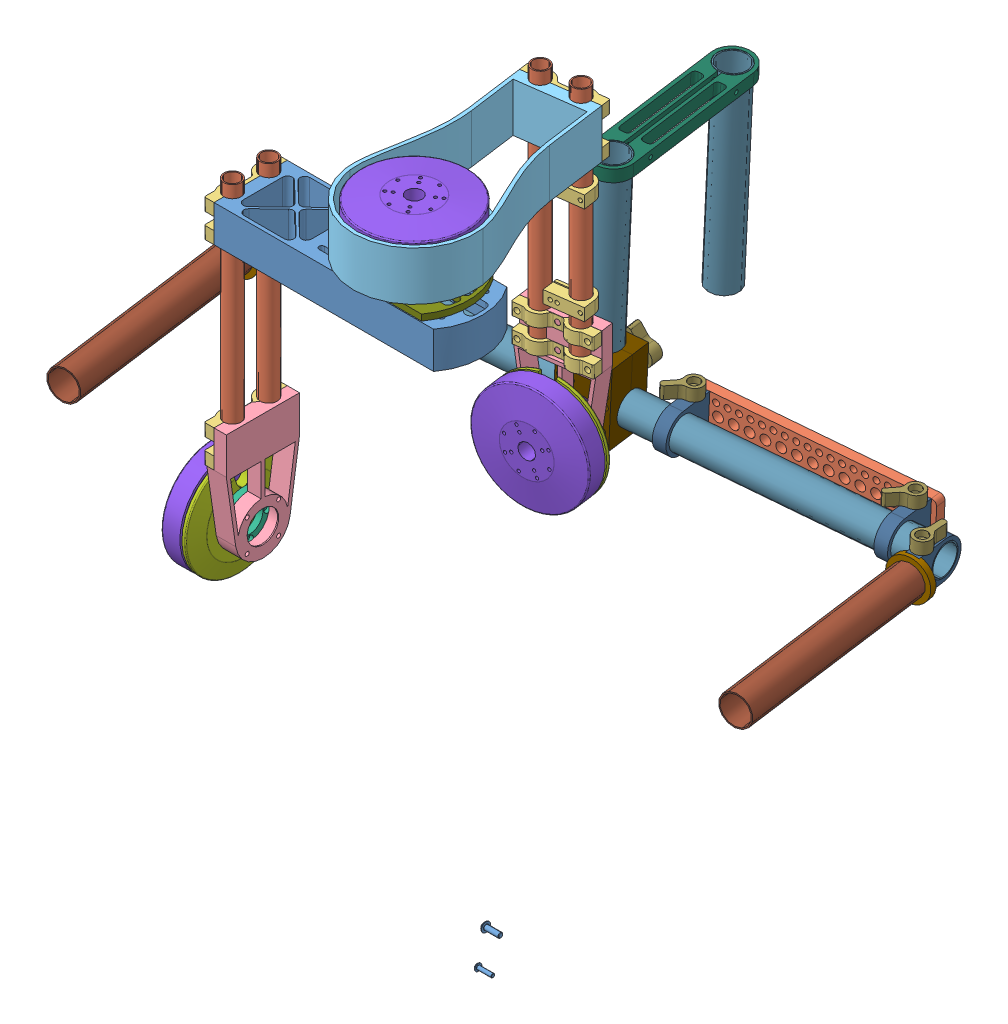
SolidWorks assembly Kinematik-3, configuration Default. Lengths in mm.
Overall size (547.61 521.51 375.61).
65 component instances, 21 part files, 73 mates.
Components (placement in the parent):
- Pitch_Roll-1: Pitch_Roll [Default] at (-118.8271 188.3671 50.6062) size (200.1 272.5 60)
  - Axis_roll-1: Axis_roll [Default] at (-7.781 -12.9874 24.4541) size (190 30 60)
  - Pipe_14mm-1: Pipe_14mm [200mm] at (-7.781 -172.9874 9.3541) size (14 200 14)
  - Pipe_14mm-2: Pipe_14mm [200mm] at (-7.781 -172.9874 -20.4459) x (0.999247 0 -0.038789) z (0.038789 0 0.999247) size (14 200 14)
  - Scoba_dowble-1: Scoba_dowble [Default] at (-7.781 7.0126 24.4541) size (10.1 10 60)
  - Scoba_dowble-4: Scoba_dowble [Default] at (-7.781 -12.9874 24.4541) size (10.1 10 60)
  - Axis_pitch-1: Axis_pitch [Default] at (-13.681 -142.9874 -35.5459) x (0 1 0) z (0 0 -1) size (102.5 16 60)
  - Scoba_dowble-5: Scoba_dowble [Default] at (-7.781 -152.9874 24.4541) size (10.1 10 60)
  - Scoba_dowble-6: Scoba_dowble [Default] at (-7.781 -172.9874 24.4541) size (10.1 10 60)
- Vert_rod_Yaw-1: Vert_rod_Yaw [Default] at (-64.2912 186.0394 -87.2214) x (0.99099 0 -0.133938) z (0.133938 0 0.99099) size (115.95 200 208.08)
  - Vert_rod-1: Vert_rod [Default] at (23.4777 34.3403 0.7123) size (100.16 40 190)
  - Pipe_14mm-1: Pipe_14mm [200mm] at (38.5777 84.3403 0.7123) x (0.837169 0 0.546944) z (0.546944 0 -0.837169) size (14 200 14)
  - Pipe_14mm-2: Pipe_14mm [200mm] at (68.3777 84.3403 0.7123) x (0.837169 0 0.546944) z (0.546944 0 -0.837169) size (14 200 14)
  - Scoba_dowble-1: Scoba_dowble [Default] at (23.4777 34.3403 0.7123) x (0 0 1) z (-1 0 0) size (10.1 10 60)
  - Scoba_dowble-2: Scoba_dowble [Default] at (83.4777 74.3403 0.7123) x (0 0 1) z (1 0 0) size (10.1 10 60)
  - Washer_bearings-1: Washer_bearings [Default] at (53.4777 45.3403 140.7123) x (0.707107 0 0.707107) z (-0.707107 0 0.707107) size (40.8 5 40.8)
  - Motor8190_DYS-1: Motor8190_DYS [Default] at (39.267 74.8347 138.3821) x (-1 0 0) z (0 0 1) size (115.95 27.6 115.95)
    - Stator-1: Stator [Default] at (-14.2107 17.4944 2.3302) size (87 7.3 86.61)
    - Rotor-1: Rotor [Default] at (-14.2107 15.8944 2.3302) x (0.429925 0 -0.902864) z (0 1 0) size (87 87 27.6)
- Washer_bearings-1: Washer_bearings [Default] at (-127.5081 -34.6203 45.0604) x (0 -0.707107 -0.707107) z (0 0.707107 -0.707107) size (40.8 5 40.8)
- Motor8190_DYS-1: Motor8190_DYS [Default] at (-157.0025 -32.2901 30.8496) x (0 0 -1) z (0 -1 0) size (115.95 27.6 115.95)
  - Stator-1: Stator [Default] at (-14.2107 17.4944 2.3302) size (87 7.3 86.61)
  - Rotor-1: Rotor [Default] at (-14.2107 15.8944 2.3302) x (0.429925 0 -0.902864) z (0 1 0) size (87 87 27.6)
- Axis_pitch-1: Axis_pitch [Default] at (-40.1394 100.3797 -83.8132) x (0 1 0) z (-0.99099 0 0.133938) size (102.5 16 60)
- Scoba_dowble-1: Scoba_dowble [Default] at (18.5497 90.3797 -97.547) x (-0.130612 0 -0.991434) z (0.991434 0 -0.130612) size (10.1 10 60)
- Scoba_dowble-2: Scoba_dowble [Default] at (-40.9296 80.3797 -89.6601) x (-0.133938 0 -0.99099) z (-0.99099 0 0.133938) size (10.1 10 60)
- Washer_bearings-2: Washer_bearings [Default] at (-11.0794 20.3797 -92.7863) x (-0.700736 -0.707107 0.094708) z (-0.700736 0.707107 0.094708) size (40.8 5 40.8)
- Motor8190_DYS-2: Motor8190_DYS [Default] at (-21.2116 22.7099 -61.6543) x (-0.99099 0 0.133938) z (0 -1 0) size (115.95 27.6 115.95)
  - Stator-1: Stator [Default] at (-14.2107 17.4944 2.3302) size (87 7.3 86.61)
  - Rotor-1: Rotor [Default] at (-14.2107 15.8944 2.3302) x (0.429925 0 -0.902864) z (0 1 0) size (87 87 27.6)
- Grip-1: Grip [Default] at (226.4049 11.0442 -120.6156) x (-0.990067 0.043147 0.133813) z (-0.042759 -0.999069 0.005779) size (33 209.05 42.22)
  - Bottom grip-1: Bottom grip [Default] at (-5.748 16.1796 1.2127) size (33 35 33)
  - Top grip-1: Top grip [Default] at (-10.748 22.1796 0.9885) size (10 41.05 31)
  - Pipe_d25x1mm-1: Pipe_d25x1mm [Default] at (-5.748 -148.8204 1.2127) size (25 165 25)
  - Flag_Vlad_kletka-1: Flag_Vlad_kletka [Радиус 20мм] at (-5.748 28.1796 -14.5115) x (-0.996402 -0.084754 0) z (0.084754 -0.996402 0) size (14 10 27)
  - socket head cap screw_din-3: socket head cap screw_din [DIN 912 M3 x 8 --- 8N] at (-5.748 13.1796 -3.0373) x (0 1 0) z (0 0 1) size (11 5.5 5.5)
  - socket head cap screw_din-4: socket head cap screw_din [DIN 912 M3 x 8 --- 8N] at (-5.748 13.1796 5.4627) x (0 1 0) z (0 0 1) size (11 5.5 5.5)
- Grip-2: Grip [Default] at (-258.7279 32.1864 -55.0472) x (-0.990067 0.043147 0.133813) z (-0.042759 -0.999069 0.005779) size (33 209.05 42.22)
  - Bottom grip-1: Bottom grip [Default] at (-5.748 16.1796 1.2127) size (33 35 33)
  - Top grip-1: Top grip [Default] at (-10.748 22.1796 0.9885) size (10 41.05 31)
  - Pipe_d25x1mm-1: Pipe_d25x1mm [Default] at (-5.748 -148.8204 1.2127) size (25 165 25)
  - Flag_Vlad_kletka-1: Flag_Vlad_kletka [Радиус 20мм] at (-5.748 28.1796 -14.5115) x (-0.996402 -0.084754 0) z (0.084754 -0.996402 0) size (14 10 27)
  - socket head cap screw_din-3: socket head cap screw_din [DIN 912 M3 x 8 --- 8N] at (-5.748 13.1796 -3.0373) x (0 1 0) z (0 0 1) size (11 5.5 5.5)
  - socket head cap screw_din-4: socket head cap screw_din [DIN 912 M3 x 8 --- 8N] at (-5.748 13.1796 5.4627) x (0 1 0) z (0 0 1) size (11 5.5 5.5)
- Pipe_25mm-1: Pipe_25mm [Length_500mm] at (-264.0205 31.1665 -99.4681) x (-0.140188 -0.230405 -0.962944) z (-0.010717 -0.972138 0.234165) size (25 500 25)
- Pipe_25mm-2: Pipe_25mm [Length_160mm] at (-15.8838 34.8662 -133.0052) x (-0.017846 -0.00502 -0.999828) z (0.998926 -0.042854 -0.017615) size (25 160 25)
- Plate_for_vert_hand_Serega-1: Plate_for_vert_hand_Serega [С увеличеными зазорами] at (-24.8729 184.7265 -247.8359) x (0.042759 0.999069 -0.005779) z (0.990067 -0.043147 -0.133813) size (10 146 31)
- Pipe_25mm-4: Pipe_25mm [Length_160mm] at (-31.2867 34.8662 -246.969) x (0.874935 -0.034652 0.482999) z (-0.482349 0.025709 0.875602) size (25 160 25)
- Plate_roll-1: Plate_roll [Default] at (-37.0314 205.3797 75.0604) size (89.17 5 60)
- Axis_D20mm-1: Axis_D20mm [Default] at (7.5514 210.3797 45.0604) size (20 25 20)
- Axis_D20mm-2: Axis_D20mm [Default] at (-13.892 20.3797 -113.5971) x (0.990669 0.025428 -0.133894) z (0.025199 -0.999677 -0.003406) size (20 25 20)
- Clip_bottom-1: Clip_bottom [Bottom] at (4.992 -0.9857 -120.1858) x (-0.990067 0.043147 0.133813) z (-0.042759 -0.999069 0.005779) size (41 19.5 59)
- Clip_bottom-2: Clip_bottom [Top] at (-39.7528 0.7833 -145.4201) x (0.990067 -0.043147 -0.133813) z (-0.042759 -0.999069 0.005779) size (41 15.5 59)
- Flag_Vlad_kletka-1: Flag_Vlad_kletka [Радиус 20мм] at (-1.1018 45.1918 -150.644) x (-0.798143 -0.592733 0.107873) z (0.587392 -0.805399 -0.079389) size (14 10 27)
- Flag_Vlad_kletka-2: Flag_Vlad_kletka [Радиус 20мм] at (-33.873 46.62 -146.2148) x (0.615598 -0.783656 -0.083201) z (0.776595 0.621195 -0.104961) size (14 10 27)
- Flag_Vlad_kletka-3: Flag_Vlad_kletka [Радиус 20мм] at (-19.2875 3.8451 -148.1861) x (-0.806851 0.580602 0.10905) z (-0.575371 -0.814188 0.077765) size (14 10 27)
- socket button head screw_iso-1: socket button head screw_iso [ISO 7380 - M4 x 12 --- 12N] at (50.7675 -240.9595 31.6019) size (14.2 7.6 7.6)
- socket button head screw_iso-2: socket button head screw_iso [ISO 7380 - M3 x 12 --- 12N] at (69.3814 -248.2768 55.9877) size (13.65 5.7 5.7)
- Plate_utilites-1: Plate_utilites [Default] at (24.6908 33.9497 -164.2714) x (0.990067 -0.043147 -0.133813) z (0.042759 0.999069 -0.005779) size (179.6 8 31)
- Top grip-1: Top grip [Default] at (188.3899 11.3188 -183.369) x (0.990067 -0.043147 -0.133813) z (-0.042759 -0.999069 0.005779) size (10 41.05 31)
- Flag_Vlad_kletka-4: Flag_Vlad_kletka [Радиус 20мм] at (194.8066 26.5886 -178.1817) x (-0.807024 0.031128 -0.589698) z (0.588969 -0.029878 -0.807603) size (14 10 27)
- Top grip-2: Top grip [Default] at (28.3902 18.2916 -161.7441) x (0.990067 -0.043147 -0.133813) z (-0.042759 -0.999069 0.005779) size (10 41.05 31)
- Flag_Vlad_kletka-5: Flag_Vlad_kletka [Радиус 20мм] at (34.8069 33.5614 -156.5568) x (-0.807024 0.031128 -0.589698) z (0.588969 -0.029878 -0.807603) size (14 10 27)
- Grip_plate_akk-1: Grip_plate_akk [Default] at (3.5658 110.3797 -95.6739) x (0 1 0) z (-0.99099 0 0.133938) size (10 20.2 30.2)
- Grip_plate_akk-2: Grip_plate_akk [Default] at (3.5658 190.3797 -95.6739) x (0 1 0) z (-0.99099 0 0.133938) size (10 20.2 30.2)
Mates (geometry in assembly coordinates):
- Совпадение1: coincident anti-aligned: plane of Pitch_Roll-1/Axis_pitch-1 through (-127.5081 -34.6203 45.0604) normal (-1 0 0); plane of Washer_bearings-1 through (-127.5081 -34.6203 45.0604) normal (1 0 0)
- Концентричный8: concentric aligned: cylinder of Washer_bearings-1 through (-127.5081 -19.6203 45.0604) axis (1 0 0) radius 1.7; cylinder of Motor8190_DYS-1/Stator-1 through (-132.5081 -19.6203 45.0604) axis (1 0 0) radius 1.25
- Концентричный9: concentric aligned: cylinder of Washer_bearings-1 through (-127.5081 -49.6203 45.0604) axis (1 0 0) radius 1.7; cylinder of Motor8190_DYS-1/Stator-1 through (-132.5081 -49.6203 45.0604) axis (1 0 0) radius 1.25
- Совпадение4: coincident anti-aligned: plane of Washer_bearings-1 through (-132.5081 -34.6203 45.0604) normal (-1 0 0); plane of Motor8190_DYS-1/Stator-1 through (-132.5081 -34.6203 75.0604) normal (1 0 0)
- Совпадение5: coincident aligned: plane of Vert_rod_Yaw-1/Pipe_14mm-2 through (3.5658 70.3797 -95.6739) normal (0 -1 0); circle of Axis_pitch-1
- Совпадение6: coincident aligned: plane of Axis_pitch-1 through (-42.2824 100.3797 -99.6691) normal (0 1 0); plane of Scoba_dowble-1 through (3.5791 100.3797 -95.5748) normal (0 1 0)
- Совпадение7: coincident aligned: plane of Vert_rod_Yaw-1/Pipe_14mm-1 through (-25.9656 70.3797 -91.6825) normal (0 -1 0); plane of Scoba_dowble-2 through (-25.9656 70.3797 -91.6825) normal (0 -1 0)
- Концентричный19: concentric aligned: cylinder of Axis_pitch-1 through (1.7091 33.2844 -94.5147) axis (0.133938 0 0.99099) radius 1.7; cylinder of Washer_bearings-2 through (2.3788 33.2844 -89.5598) axis (0.133938 0 0.99099) radius 1.25
- Концентричный20: concentric aligned: cylinder of Washer_bearings-2 through (-23.1981 7.475 -86.1029) axis (0.133938 0 0.99099) radius 1.25; cylinder of Axis_pitch-1 through (-23.8678 7.475 -91.0579) axis (0.133938 0 0.99099) radius 1.7
- Совпадение8: coincident anti-aligned: plane of Axis_pitch-1 through (-11.0794 20.3797 -92.7863) normal (0.133938 0 0.99099); plane of Washer_bearings-2 through (-11.0794 20.3797 -92.7863) normal (-0.133938 0 -0.99099)
- Концентричный21: concentric aligned: cylinder of Washer_bearings-2 through (-11.0794 35.3797 -92.7863) axis (-0.133938 0 -0.99099) radius 1.7; cylinder of Motor8190_DYS-2/Stator-1 through (-10.4097 35.3797 -87.8314) axis (-0.133938 0 -0.99099) radius 1.25
- Концентричный22: concentric aligned: cylinder of Washer_bearings-2 through (-11.0794 5.3797 -92.7863) axis (-0.133938 0 -0.99099) radius 1.7; cylinder of Motor8190_DYS-2/Stator-1 through (-10.4097 5.3797 -87.8314) axis (-0.133938 0 -0.99099) radius 1.25
- Совпадение9: coincident anti-aligned: plane of Washer_bearings-2 through (-10.4097 20.3797 -87.8314) normal (0.133938 0 0.99099); plane of Motor8190_DYS-2/Stator-1 through (19.32 20.3797 -91.8495) normal (-0.133938 0 -0.99099)
- Концентричный23: concentric aligned: cylinder of Axis_pitch-1 through (-25.9656 70.3797 -91.6825) axis (0 1 0) radius 7.1; cylinder of Vert_rod_Yaw-1/Pipe_14mm-1 through (-25.9656 70.3797 -91.6825) axis (0 1 0) radius 7
- Концентричный24: concentric aligned: cylinder of Axis_pitch-1 through (3.5658 70.3797 -95.6739) axis (0 1 0) radius 7.1; cylinder of Vert_rod_Yaw-1/Pipe_14mm-2 through (3.5658 70.3797 -95.6739) axis (0 1 0) radius 7
- Концентричный25: concentric aligned: cylinder of Scoba_dowble-2 through (3.5658 70.3797 -95.6739) axis (0 1 0) radius 7.1; cylinder of Vert_rod_Yaw-1/Pipe_14mm-2 through (3.5658 70.3797 -95.6739) axis (0 1 0) radius 7
- Концентричный26: concentric aligned: cylinder of Scoba_dowble-2 through (-25.9656 70.3797 -91.6825) axis (0 1 0) radius 7.1; cylinder of Vert_rod_Yaw-1/Pipe_14mm-1 through (-25.9656 70.3797 -91.6825) axis (0 1 0) radius 7
- Касательность2: tangent aligned: cylinder of Scoba_dowble-1 through (3.5791 100.3797 -95.5748) axis (0 -1 0) radius 7.1; cylinder of Vert_rod_Yaw-1/Pipe_14mm-2 through (3.5658 70.3797 -95.6739) axis (0 1 0) radius 7
- Концентричный27: concentric anti-aligned: cylinder of Scoba_dowble-1 through (-25.9656 100.3797 -91.6825) axis (0 -1 0) radius 7.1; cylinder of Vert_rod_Yaw-1/Pipe_14mm-1 through (-25.9656 70.3797 -91.6825) axis (0 1 0) radius 7
- Концентричный28: concentric anti-aligned: cylinder of Grip-1/Top grip-1 through (221.1122 10.0244 -165.0365) axis (0.990067 -0.043147 -0.133813) radius 12.55; cylinder of Pipe_25mm-1 through (231.0129 9.5929 -166.3747) axis (-0.990067 0.043147 0.133813) radius 12.5
- Совпадение10: coincident aligned: plane of Grip-1/Top grip-1 through (231.0129 9.5929 -166.3747) normal (0.990067 -0.043147 -0.133813); plane of Pipe_25mm-1 through (231.0129 9.5929 -166.3747) normal (0.990067 -0.043147 -0.133813)
- Концентричный29: concentric anti-aligned: cylinder of Grip-2/Top grip-1 through (-264.0205 31.1665 -99.4681) axis (0.990067 -0.043147 -0.133813) radius 12.55; cylinder of Pipe_25mm-1 through (231.0129 9.5929 -166.3747) axis (-0.990067 0.043147 0.133813) radius 12.5
- Совпадение11: coincident aligned: plane of Grip-2/Top grip-1 through (-264.0205 31.1665 -99.4681) normal (-0.990067 0.043147 0.133813); plane of Pipe_25mm-1 through (-264.0205 31.1665 -99.4681) normal (-0.990067 0.043147 0.133813)
- Концентричный34: concentric anti-aligned: cylinder of Pipe_25mm-2 through (-9.0425 194.7172 -133.9298) axis (-0.042759 -0.999069 0.005779) radius 12.5; cylinder of Plate_for_vert_hand_Serega-1 through (-9.4701 184.7265 -133.8721) axis (0.042759 0.999069 -0.005779) radius 12.6
- Совпадение18: coincident aligned: plane of Pipe_25mm-2 through (-9.0425 194.7172 -133.9298) normal (0.042759 0.999069 -0.005779); plane of Plate_for_vert_hand_Serega-1 through (-9.0425 194.7172 -133.9298) normal (0.042759 0.999069 -0.005779)
- Концентричный36: concentric anti-aligned: cylinder of Plate_for_vert_hand_Serega-1 through (-24.8729 184.7265 -247.8359) axis (0.042759 0.999069 -0.005779) radius 12.6; cylinder of Pipe_25mm-4 through (-24.4453 194.7172 -247.8937) axis (-0.042759 -0.999069 0.005779) radius 12.5
- Совпадение21: coincident aligned: plane of Plate_for_vert_hand_Serega-1 through (-9.0425 194.7172 -133.9298) normal (0.042759 0.999069 -0.005779); plane of Pipe_25mm-4 through (-24.4453 194.7172 -247.8937) normal (0.042759 0.999069 -0.005779)
- Параллельность6: parallel aligned: plane of Pitch_Roll-1/Axis_roll-1 through (-126.6081 205.3797 15.0604) normal (0 0 -1); plane of Plate_roll-1 through (-37.0314 210.3797 15.8604) normal (0 0 -1)
- Совпадение23: coincident anti-aligned: plane of Pitch_Roll-1/Axis_roll-1 through (-126.6081 205.3797 59.9604) normal (0 1 0); plane of Plate_roll-1 through (12.9686 205.3797 45.0604) normal (0 -1 0)
- Концентричный38: concentric anti-aligned: cylinder of Plate_roll-1 through (7.5514 205.3797 45.0604) axis (0 1 0) radius 15; cylinder of Axis_D20mm-1 through (7.5514 235.3797 45.0604) axis (0 -1 0) radius 10
- Совпадение24: coincident anti-aligned: plane of Plate_roll-1 through (12.9686 210.3797 45.0604) normal (0 1 0); plane of Axis_D20mm-1 through (7.5514 210.3797 45.0604) normal (0 -1 0)
- Концентричный39: concentric anti-aligned: cylinder of Vert_rod_Yaw-1/Motor8190_DYS-1/Rotor-1 through (7.5514 244.9797 45.0604) axis (0 1 0) radius 6.5; cylinder of Axis_D20mm-1 through (7.5514 235.3797 45.0604) axis (0 -1 0) radius 10
- Совпадение25: coincident anti-aligned: plane of Vert_rod_Yaw-1/Motor8190_DYS-1/Rotor-1 through (7.5514 235.3797 45.0604) normal (0 -1 0); plane of Axis_D20mm-1 through (7.5514 235.3797 45.0604) normal (0 1 0)
- Ширина2: width anti-aligned: plane of Pitch_Roll-1/Axis_roll-1 through (47.8085 150.56 29.3104) normal (0 0 -1); plane of Pitch_Roll-1/Axis_roll-1 through (47.8085 150.56 24.8104) normal (0 0 1); cylinder of Plate_roll-1 through (36.5514 205.3797 27.0604) axis (0 -1 0) radius 1.65
- Концентричный40: concentric anti-aligned: cylinder of Motor8190_DYS-2/Rotor-1 through (-9.2578 20.3797 -79.3089) axis (0.133938 0 0.99099) radius 6.5; cylinder of Axis_D20mm-2 through (-10.5436 20.3797 -88.8224) axis (-0.133938 0 -0.99099) radius 10
- Совпадение26: coincident anti-aligned: plane of Motor8190_DYS-2/Rotor-1 through (-10.5436 20.3797 -88.8224) normal (-0.133938 0 -0.99099); plane of Axis_D20mm-2 through (-10.5436 20.3797 -88.8224) normal (0.133938 0 0.99099)
- Концентричный41: concentric anti-aligned: cylinder of Pipe_25mm-1 through (231.0129 9.5929 -166.3747) axis (-0.990067 0.043147 0.133813) radius 12.5; cylinder of Clip_bottom-1 through (-36.8002 21.2642 -130.1782) axis (0.990067 -0.043147 -0.133813) radius 12.6
- Концентричный42: concentric anti-aligned: cylinder of Pipe_25mm-2 through (-9.0425 194.7172 -133.9298) axis (-0.042759 -0.999069 0.005779) radius 12.5; cylinder of Clip_bottom-1 through (-16.5038 20.3797 -132.9214) axis (0.042759 0.999069 -0.005779) radius 12.6
- Ширина3: width anti-aligned: plane of Pipe_25mm-1 through (231.0129 9.5929 -166.3747) normal (0.990067 -0.043147 -0.133813); plane of Pipe_25mm-1 through (-264.0205 31.1665 -99.4681) normal (-0.990067 0.043147 0.133813); plane of Clip_bottom-1 through (-35.154 59.7284 -130.4007) normal (-0.990067 0.043147 0.133813); plane of Clip_bottom-1 through (3.2581 7.0068 -135.5923) normal (0.990067 -0.043147 -0.133813)
- Параллельность7: parallel anti-aligned: line of Grip-1/Top grip-1 through (235.0977 25.0784 -141.1444) axis (-0.133938 0 -0.99099); line of Clip_bottom-1 through (2.916 -0.9857 -135.5461) axis (0.133938 0 0.99099)
- Совпадение28: coincident aligned: plane of Grip-1/Top grip-1 through (224.7953 25.5099 -142.7793) normal (0.042759 0.999069 -0.005779); plane of Grip-2/Top grip-1 through (-260.3375 46.6521 -77.2109) normal (0.042759 0.999069 -0.005779)
- Концентричный43: concentric aligned: cylinder of Pipe_25mm-1 through (231.0129 9.5929 -166.3747) axis (-0.990067 0.043147 0.133813) radius 12.5; cylinder of Clip_bottom-2 through (3.7925 19.4952 -135.6646) axis (-0.990067 0.043147 0.133813) radius 12.6
- Совпадение29: coincident aligned: plane of Clip_bottom-1 through (-29.7562 0.4381 -131.1303) normal (-0.042759 -0.999069 0.005779); plane of Clip_bottom-2 through (-5.0045 -0.6405 -134.4756) normal (-0.042759 -0.999069 0.005779)
- Совпадение30: coincident aligned: plane of Clip_bottom-1 through (3.2581 7.0068 -135.5923) normal (0.990067 -0.043147 -0.133813); plane of Clip_bottom-2 through (5.4387 57.9593 -135.8871) normal (0.990067 -0.043147 -0.133813)
- Расстояние1: distance = 24 mm anti-aligned: plane of Clip_bottom-2 through (-35.154 59.7284 -130.4007) normal (0.042759 0.999069 -0.005779); plane of Pipe_25mm-2 through (-15.8838 34.8662 -133.0052) normal (-0.042759 -0.999069 0.005779)
- Концентричный44: concentric anti-aligned: cylinder of Axis_D20mm-2 through (-10.5436 20.3797 -88.8224) axis (-0.133938 0 -0.99099) radius 10; circle of Clip_bottom-1
- Совпадение33: coincident anti-aligned: plane of Axis_D20mm-2 through (-13.892 20.3797 -113.5971) normal (-0.133938 0 -0.99099); plane of Clip_bottom-1 through (5.5278 -0.9857 -116.2218) normal (0.133938 0 0.99099)
- Концентричный45: concentric aligned: cylinder of Clip_bottom-2 through (0.9743 45.1918 -135.2837) axis (-0.133938 0 -0.99099) radius 2.25; cylinder of Flag_Vlad_kletka-1 through (-2.4412 45.1918 -160.5539) axis (-0.133938 0 -0.99099) radius 1.65
- Совпадение34: coincident anti-aligned: plane of Clip_bottom-2 through (-39.7528 0.7833 -145.4201) normal (-0.133938 0 -0.99099); plane of Flag_Vlad_kletka-1 through (-1.1018 45.1918 -150.644) normal (0.133938 0 0.99099)
- Концентричный46: concentric aligned: cylinder of Clip_bottom-2 through (-31.797 46.62 -130.8545) axis (-0.133938 0 -0.99099) radius 2.25; cylinder of Flag_Vlad_kletka-2 through (-35.2124 46.62 -156.1247) axis (-0.133938 0 -0.99099) radius 1.65
- Совпадение35: coincident anti-aligned: plane of Clip_bottom-2 through (-39.7528 0.7833 -145.4201) normal (-0.133938 0 -0.99099); plane of Flag_Vlad_kletka-2 through (-33.873 46.62 -146.2148) normal (0.133938 0 0.99099)
- Концентричный47: concentric aligned: cylinder of Clip_bottom-2 through (-17.2115 3.8451 -132.8258) axis (-0.133938 0 -0.99099) radius 2.25; cylinder of Flag_Vlad_kletka-3 through (-20.6269 3.8451 -158.096) axis (-0.133938 0 -0.99099) radius 1.65
- Совпадение36: coincident anti-aligned: plane of Clip_bottom-2 through (-39.7528 0.7833 -145.4201) normal (-0.133938 0 -0.99099); plane of Flag_Vlad_kletka-3 through (-19.2875 3.8451 -148.1861) normal (0.133938 0 0.99099)
- Параллельность8: parallel aligned: plane of Plate_for_vert_hand_Serega-1 through (6.3036 194.0484 -136.0039) normal (0.990067 -0.043147 -0.133813); plane of Clip_bottom-2 through (5.4387 57.9593 -135.8871) normal (0.990067 -0.043147 -0.133813)
- Концентричный48: concentric aligned: cylinder of Pipe_25mm-1 through (231.0129 9.5929 -166.3747) axis (-0.990067 0.043147 0.133813) radius 12.5; cylinder of Top grip-1 through (201.3109 10.8873 -162.3603) axis (-0.990067 0.043147 0.133813) radius 12.55
- Расстояние3: distance = 30 mm aligned: plane of Top grip-1 through (201.3109 10.8873 -162.3603) normal (0.990067 -0.043147 -0.133813); plane of Pipe_25mm-1 through (231.0129 9.5929 -166.3747) normal (0.990067 -0.043147 -0.133813)
- Перпендикулярность1: perpendicular: plane of Grip-1/Top grip-1 through (223.4698 -5.4612 -142.6001) normal (-0.042759 -0.999069 0.005779); plane of Top grip-1 through (187.9881 11.3188 -186.3419) normal (-0.133938 0 -0.99099)
- Совпадение37: coincident anti-aligned: plane of Plate_utilites-1 through (24.6908 33.9497 -164.2714) normal (0.133938 0 0.99099); plane of Top grip-1 through (187.9881 11.3188 -186.3419) normal (-0.133938 0 -0.99099)
- Расстояние6: distance = 14 mm anti-aligned: plane of Plate_utilites-1 through (200.1148 -4.7709 -196.0537) normal (0.990067 -0.043147 -0.133813); plane of Top grip-1 through (191.4102 11.3188 -161.0221) normal (-0.990067 0.043147 0.133813)
- Совпадение39: coincident aligned: plane of Plate_utilites-1 through (201.4403 26.2003 -196.2328) normal (0.042759 0.999069 -0.005779); plane of Top grip-1 through (198.9533 26.3729 -184.7967) normal (0.042759 0.999069 -0.005779)
- Концентричный49: concentric aligned: cylinder of Top grip-1 through (193.209 -10.7406 -177.9657) axis (0.042759 0.999069 -0.005779) radius 2.25; cylinder of Flag_Vlad_kletka-4 through (195.2342 36.5793 -178.2394) axis (0.042759 0.999069 -0.005779) radius 1.65
- Совпадение40: coincident anti-aligned: plane of Top grip-1 through (198.9533 26.3729 -184.7967) normal (0.042759 0.999069 -0.005779); plane of Flag_Vlad_kletka-4 through (194.8066 26.5886 -178.1817) normal (-0.042759 -0.999069 0.005779)
- Концентричный50: concentric aligned: cylinder of Pipe_25mm-1 through (231.0129 9.5929 -166.3747) axis (-0.990067 0.043147 0.133813) radius 12.5; cylinder of Top grip-2 through (41.3111 17.8601 -140.7354) axis (-0.990067 0.043147 0.133813) radius 12.55
- Совпадение41: coincident anti-aligned: plane of Plate_utilites-1 through (24.6908 33.9497 -164.2714) normal (0.133938 0 0.99099); plane of Top grip-2 through (27.9883 18.2916 -164.7171) normal (-0.133938 0 -0.99099)
- Расстояние7: distance = 14 mm anti-aligned: plane of Top grip-2 through (41.3111 17.8601 -140.7354) normal (0.990067 -0.043147 -0.133813); plane of Plate_utilites-1 through (23.6193 33.9497 -172.1993) normal (-0.990067 0.043147 0.133813)
- Концентричный51: concentric aligned: cylinder of Top grip-2 through (33.2092 -3.7677 -156.3409) axis (0.042759 0.999069 -0.005779) radius 2.25; cylinder of Flag_Vlad_kletka-5 through (35.2345 43.5521 -156.6146) axis (0.042759 0.999069 -0.005779) radius 1.65
- Совпадение42: coincident anti-aligned: plane of Top grip-2 through (38.9536 33.3457 -163.1718) normal (0.042759 0.999069 -0.005779); plane of Flag_Vlad_kletka-5 through (34.8069 33.5614 -156.5568) normal (-0.042759 -0.999069 0.005779)
- Концентричный52: concentric anti-aligned: cylinder of Vert_rod_Yaw-1/Pipe_14mm-2 through (3.5658 70.3797 -95.6739) axis (0 1 0) radius 7; cylinder of Grip_plate_akk-1 through (3.5658 120.3797 -95.6739) axis (0 -1 0) radius 7.1
- Расстояние8: distance = 10 mm anti-aligned: plane of Grip_plate_akk-1 through (3.5658 110.3797 -95.6739) normal (0 -1 0); plane of Axis_pitch-1 through (-42.2824 100.3797 -99.6691) normal (0 1 0)
- Параллельность9: parallel anti-aligned: plane of Axis_pitch-1 through (-12.5527 20.3797 -103.6872) normal (-0.133938 0 -0.99099); plane of Grip_plate_akk-1 through (14.9276 120.3797 -87.0177) normal (0.133938 0 0.99099)
- Концентричный53: concentric anti-aligned: cylinder of Vert_rod_Yaw-1/Pipe_14mm-2 through (3.5658 70.3797 -95.6739) axis (0 1 0) radius 7; cylinder of Grip_plate_akk-2 through (3.5658 200.3797 -95.6739) axis (0 -1 0) radius 7.1
- Параллельность10: parallel anti-aligned: plane of Axis_pitch-1 through (-12.5527 20.3797 -103.6872) normal (-0.133938 0 -0.99099); plane of Grip_plate_akk-2 through (14.9276 200.3797 -87.0177) normal (0.133938 0 0.99099)
- Расстояние10: distance = 70 mm anti-aligned: plane of Grip_plate_akk-2 through (3.5658 190.3797 -95.6739) normal (0 -1 0); plane of Grip_plate_akk-1 through (3.5658 120.3797 -95.6739) normal (0 1 0)
